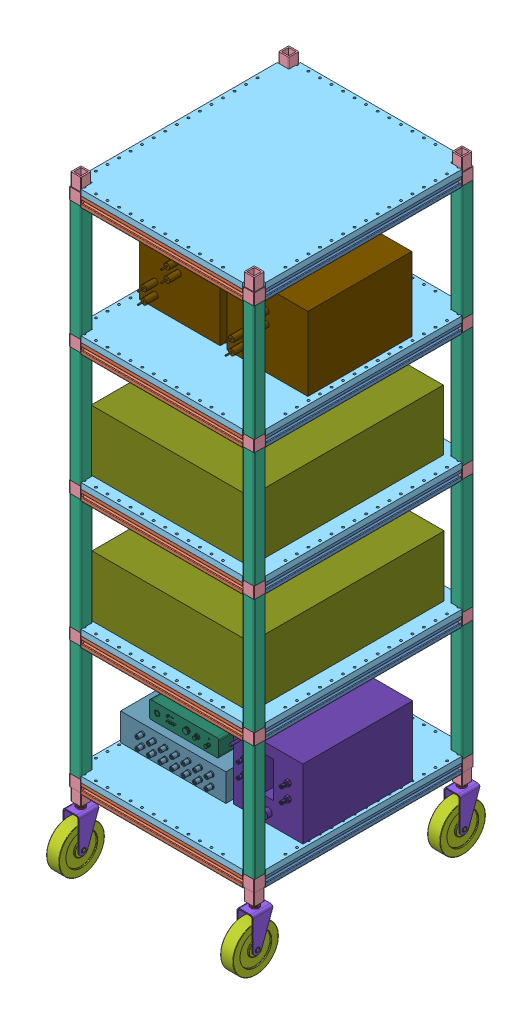
SolidWorks assembly Frame V2, configuration Default. Lengths in mm.
Overall size (421.16 1328.12 562.5).
122 component instances, 18 part files, 99 mates.
Components (placement in the parent):
- Rack Level V2-1: Rack Level V2 [Default] at (-142.0534 42.1379 2.242) size (406.56 81.28 482.6)
  - connector_rod_17in-1: connector_rod_17in [Default] at (244.6451 248.7296 254.5249) size (25.4 25.4 431.8)
  - connector_rod_17in-2: connector_rod_17in [Default] at (623.9342 246.0174 254.5249) size (25.4 25.4 431.8)
  - connector_rod_14in-1: connector_rod_14in [Default] at (435.1457 246.5198 483.1249) x (0 0 -1) z (1 0 0) size (25.4 25.4 355.6)
  - connector_rod_14in-2: connector_rod_14in [Default] at (434.9859 248.2272 25.9249) x (0 0 -1) z (1 0 0) size (25.4 25.4 355.6)
  - corner_bracket8-1: corner_bracket8 [Default] at (257.3451 248.4784 38.6249) x (0 1 0) z (1 0 0) size (17 21.5 21.5)
  - corner_bracket8-3: corner_bracket8 [Default] at (257.3451 248.9808 470.4249) x (0 1 0) z (0 0 -1) size (17 21.5 21.5)
  - corner_bracket8-4: corner_bracket8 [Default] at (611.2342 245.7662 38.6249) x (0 1 0) z (0 0 1) size (17 21.5 21.5)
  - corner_bracket8-5: corner_bracket8 [Default] at (611.2342 246.2686 470.4249) x (0 -1 0) z (0 0 -1) size (17 21.5 21.5)
  - 9215-1: 9215 [Default] at (625.4859 250.333 25.9249) x (0 1 0) z (0 0 1) size (81.28 25.4 25.4)
  - 9215-2: 9215 [Default] at (244.4859 250.333 25.9249) x (0 1 0) z (0 0 1) size (81.28 25.4 25.4)
  - 9215-3: 9215 [Default] at (244.6457 250.333 483.1249) x (0 1 0) z (0 0 1) size (81.28 25.4 25.4)
  - 9215-4: 9215 [Default] at (625.6457 250.333 483.1249) x (0 1 0) z (0 0 1) size (81.28 25.4 25.4)
- Rack Floor-1: Rack Floor [Default] at (294.7433 300.8553 258.4179) x (0 0 -1) z (1 0 0) size (482.6 12.7 406.4)
- 9000_10_CL-1: 9000_10_CL [Default] at (483.5923 559.171 485.3669) x (1 0 0) z (0 1 0) size (25.4 25.4 254)
- 9000_10_CL-2: 9000_10_CL [Default] at (483.4325 559.171 28.1669) x (1 0 0) z (0 1 0) size (25.4 25.4 254)
- 9000_10_CL-3: 9000_10_CL [Default] at (102.5923 559.171 485.3669) x (1 0 0) z (0 1 0) size (25.4 25.4 254)
- 9000_10_CL-7: 9000_10_CL [Default] at (102.4325 305.171 28.1669) x (1 0 0) z (0 -1 0) size (25.4 25.4 254)
- Assem Wheele-1: Assem Wheele [Default] at (60.7885 133.8168 -43.4718) x (1 0 0) z (0 0.022835 0.999739) size (40 156.51 100)
  - Wheel s-1: Wheel s [Default] at (42.518 38.0039 83.6543) size (28 100 100)
  - Brackets-1: Brackets [Default] at (42.518 28.7828 49.4348) x (1 0 0) z (0 -0.022835 0.999739) size (34.6 79.05 44)
  - Brussh-1: Brussh [Default] at (42.518 38.0039 83.6543) x (0 1 0) z (0 0 1) size (13.95 28 13.95)
  - Circlips-1: Circlips [Default] at (60.5355 38.0039 83.6543) x (0 0 -1) z (1 0 0) size (9.65 8.99 0.64)
  - Postt-1: Postt [Default] at (42.518 101.3114 73.0971) x (0.999012 -0.001015 0.044435) z (-0.044446 -0.022812 0.998751) size (18 43 18)
  - Shafts-1: Shafts [Default] at (23.218 38.0039 83.6543) x (0 0.999739 0.022835) z (0 -0.022835 0.999739) size (16 40 16)
- Assem Wheele-4: Assem Wheele [Default] at (60.9483 133.8168 415.4762) x (1 0 0) z (0 0.022835 0.999739) size (40 156.51 100)
  - Wheel s-1: Wheel s [Default] at (42.518 38.0039 83.6543) size (28 100 100)
  - Brackets-1: Brackets [Default] at (42.518 28.7828 49.4348) x (1 0 0) z (0 -0.022835 0.999739) size (34.6 79.05 44)
  - Brussh-1: Brussh [Default] at (42.518 38.0039 83.6543) x (0 1 0) z (0 0 1) size (13.95 28 13.95)
  - Circlips-1: Circlips [Default] at (60.5355 38.0039 83.6543) x (0 0 -1) z (1 0 0) size (9.65 8.99 0.64)
  - Postt-1: Postt [Default] at (42.518 101.3114 73.0971) x (0.999012 -0.001015 0.044435) z (-0.044446 -0.022812 0.998751) size (18 43 18)
  - Shafts-1: Shafts [Default] at (23.218 38.0039 83.6543) x (0 0.999739 0.022835) z (0 -0.022835 0.999739) size (16 40 16)
- Assem Wheele-5: Assem Wheele [Default] at (441.9483 133.8168 413.7282) x (1 0 0) z (0 0.022835 0.999739) size (40 156.51 100)
  - Wheel s-1: Wheel s [Default] at (42.518 38.0039 83.6543) size (28 100 100)
  - Brackets-1: Brackets [Default] at (42.518 28.7828 49.4348) x (1 0 0) z (0 -0.022835 0.999739) size (34.6 79.05 44)
  - Brussh-1: Brussh [Default] at (42.518 38.0039 83.6543) x (0 1 0) z (0 0 1) size (13.95 28 13.95)
  - Circlips-1: Circlips [Default] at (60.5355 38.0039 83.6543) x (0 0 -1) z (1 0 0) size (9.65 8.99 0.64)
  - Postt-1: Postt [Default] at (42.518 101.3114 73.0971) x (0.999012 -0.001015 0.044435) z (-0.044446 -0.022812 0.998751) size (18 43 18)
  - Shafts-1: Shafts [Default] at (23.218 38.0039 83.6543) x (0 0.999739 0.022835) z (0 -0.022835 0.999739) size (16 40 16)
- Assem Wheele-6: Assem Wheele [Default] at (440.0405 133.8168 -43.4718) x (1 0 0) z (0 0.022835 0.999739) size (40 156.51 100)
  - Wheel s-1: Wheel s [Default] at (42.518 38.0039 83.6543) size (28 100 100)
  - Brackets-1: Brackets [Default] at (42.518 28.7828 49.4348) x (1 0 0) z (0 -0.022835 0.999739) size (34.6 79.05 44)
  - Brussh-1: Brussh [Default] at (42.518 38.0039 83.6543) x (0 1 0) z (0 0 1) size (13.95 28 13.95)
  - Circlips-1: Circlips [Default] at (60.5355 38.0039 83.6543) x (0 0 -1) z (1 0 0) size (9.65 8.99 0.64)
  - Postt-1: Postt [Default] at (42.518 101.3114 73.0971) x (0.999012 -0.001015 0.044435) z (-0.044446 -0.022812 0.998751) size (18 43 18)
  - Shafts-1: Shafts [Default] at (23.218 38.0039 83.6543) x (0 0.999739 0.022835) z (0 -0.022835 0.999739) size (16 40 16)
- CD15_Carrier_Demodulator-1: CD15_Carrier_Demodulator [Default] at (219.1976 411.9803 266.4352) size (142.88 73.03 161.92)
- PowerLab_835-1: PowerLab_835 [Default] at (212.5296 313.5553 266.8747) size (231.78 60.32 263.58)
- BMA_200-2: BMA_200 [Default] at (219.2508 373.8803 275.2282) size (152.45 38.15 207.67)
- Rack Level V2-2: Rack Level V2 [Default] at (-142.0534 321.5379 2.242) size (406.56 81.28 482.6)
  - connector_rod_17in-1: connector_rod_17in [Default] at (244.6451 248.7296 254.5249) size (25.4 25.4 431.8)
  - connector_rod_17in-2: connector_rod_17in [Default] at (623.9342 246.0174 254.5249) size (25.4 25.4 431.8)
  - connector_rod_14in-1: connector_rod_14in [Default] at (435.1457 246.5198 483.1249) x (0 0 -1) z (1 0 0) size (25.4 25.4 355.6)
  - connector_rod_14in-2: connector_rod_14in [Default] at (434.9859 248.2272 25.9249) x (0 0 -1) z (1 0 0) size (25.4 25.4 355.6)
  - corner_bracket8-1: corner_bracket8 [Default] at (257.3451 248.4784 38.6249) x (0 1 0) z (1 0 0) size (17 21.5 21.5)
  - corner_bracket8-3: corner_bracket8 [Default] at (257.3451 248.9808 470.4249) x (0 1 0) z (0 0 -1) size (17 21.5 21.5)
  - corner_bracket8-4: corner_bracket8 [Default] at (611.2342 245.7662 38.6249) x (0 1 0) z (0 0 1) size (17 21.5 21.5)
  - corner_bracket8-5: corner_bracket8 [Default] at (611.2342 246.2686 470.4249) x (0 -1 0) z (0 0 -1) size (17 21.5 21.5)
  - 9215-1: 9215 [Default] at (625.4859 250.333 25.9249) x (0 1 0) z (0 0 1) size (81.28 25.4 25.4)
  - 9215-2: 9215 [Default] at (244.4859 250.333 25.9249) x (0 1 0) z (0 0 1) size (81.28 25.4 25.4)
  - 9215-3: 9215 [Default] at (244.6457 250.333 483.1249) x (0 1 0) z (0 0 1) size (81.28 25.4 25.4)
  - 9215-4: 9215 [Default] at (625.6457 250.333 483.1249) x (0 1 0) z (0 0 1) size (81.28 25.4 25.4)
- Rack Floor-2: Rack Floor [Default] at (294.7433 580.7577 258.4179) x (0 0 -1) z (1 0 0) size (482.6 12.7 406.4)
- O2_CO2_analyzer-2: O2_CO2_analyzer [Default] at (287.8054 593.4577 258.9533) x (0 0 1) z (-1 0 0) size (425.45 133.35 356.87)
- 9000_10_CL-8: 9000_10_CL [Default] at (483.4325 584.571 28.1669) x (1 0 0) z (0 -1 0) size (25.4 25.4 254)
- 9000_10_CL-9: 9000_10_CL [Default] at (102.4325 584.571 28.1669) x (1 0 0) z (0 -1 0) size (25.4 25.4 254)
- 9000_10_CL-11: 9000_10_CL [Default] at (483.5923 584.571 485.3669) x (1 0 0) z (0 -1 0) size (25.4 25.4 254)
- 9000_10_CL-12: 9000_10_CL [Default] at (102.5923 584.571 485.3669) x (1 0 0) z (0 -1 0) size (25.4 25.4 254)
- Flow_Control_R1-1: Flow_Control_R1 [Default] at (414.279 313.5553 264.2811) size (152.4 152.4 266.71)
- Rack Level V2-3: Rack Level V2 [Default] at (-142.0534 600.9379 2.242) size (406.56 81.28 482.6)
  - connector_rod_17in-1: connector_rod_17in [Default] at (244.6451 248.7296 254.5249) size (25.4 25.4 431.8)
  - connector_rod_17in-2: connector_rod_17in [Default] at (623.9342 246.0174 254.5249) size (25.4 25.4 431.8)
  - connector_rod_14in-1: connector_rod_14in [Default] at (435.1457 246.5198 483.1249) x (0 0 -1) z (1 0 0) size (25.4 25.4 355.6)
  - connector_rod_14in-2: connector_rod_14in [Default] at (434.9859 248.2272 25.9249) x (0 0 -1) z (1 0 0) size (25.4 25.4 355.6)
  - corner_bracket8-1: corner_bracket8 [Default] at (257.3451 248.4784 38.6249) x (0 1 0) z (1 0 0) size (17 21.5 21.5)
  - corner_bracket8-3: corner_bracket8 [Default] at (257.3451 248.9808 470.4249) x (0 1 0) z (0 0 -1) size (17 21.5 21.5)
  - corner_bracket8-4: corner_bracket8 [Default] at (611.2342 245.7662 38.6249) x (0 1 0) z (0 0 1) size (17 21.5 21.5)
  - corner_bracket8-5: corner_bracket8 [Default] at (611.2342 246.2686 470.4249) x (0 -1 0) z (0 0 -1) size (17 21.5 21.5)
  - 9215-1: 9215 [Default] at (625.4859 250.333 25.9249) x (0 1 0) z (0 0 1) size (81.28 25.4 25.4)
  - 9215-2: 9215 [Default] at (244.4859 250.333 25.9249) x (0 1 0) z (0 0 1) size (81.28 25.4 25.4)
  - 9215-3: 9215 [Default] at (244.6457 250.333 483.1249) x (0 1 0) z (0 0 1) size (81.28 25.4 25.4)
  - 9215-4: 9215 [Default] at (625.6457 250.333 483.1249) x (0 1 0) z (0 0 1) size (81.28 25.4 25.4)
- Rack Floor-3: Rack Floor [Default] at (294.7433 860.1577 258.4179) x (0 0 -1) z (1 0 0) size (482.6 12.7 406.4)
- O2_CO2_analyzer-3: O2_CO2_analyzer [Default] at (288.4244 872.8577 261.5371) x (0 0 1) z (-1 0 0) size (425.45 133.35 356.87)
- 9000_10_CL-13: 9000_10_CL [Default] at (102.5923 863.971 485.3669) x (1 0 0) z (0 -1 0) size (25.4 25.4 254)
- 9000_10_CL-14: 9000_10_CL [Default] at (102.4325 863.971 28.1669) x (1 0 0) z (0 -1 0) size (25.4 25.4 254)
- 9000_10_CL-15: 9000_10_CL [Default] at (483.4325 863.971 28.1669) x (1 0 0) z (0 -1 0) size (25.4 25.4 254)
- 9000_10_CL-16: 9000_10_CL [Default] at (483.5923 863.971 485.3669) x (1 0 0) z (0 -1 0) size (25.4 25.4 254)
- Rack Level V2-4: Rack Level V2 [Default] at (-142.0534 880.3379 2.242) size (406.56 81.28 482.6)
  - connector_rod_17in-1: connector_rod_17in [Default] at (244.6451 248.7296 254.5249) size (25.4 25.4 431.8)
  - connector_rod_17in-2: connector_rod_17in [Default] at (623.9342 246.0174 254.5249) size (25.4 25.4 431.8)
  - connector_rod_14in-1: connector_rod_14in [Default] at (435.1457 246.5198 483.1249) x (0 0 -1) z (1 0 0) size (25.4 25.4 355.6)
  - connector_rod_14in-2: connector_rod_14in [Default] at (434.9859 248.2272 25.9249) x (0 0 -1) z (1 0 0) size (25.4 25.4 355.6)
  - corner_bracket8-1: corner_bracket8 [Default] at (257.3451 248.4784 38.6249) x (0 1 0) z (1 0 0) size (17 21.5 21.5)
  - corner_bracket8-3: corner_bracket8 [Default] at (257.3451 248.9808 470.4249) x (0 1 0) z (0 0 -1) size (17 21.5 21.5)
  - corner_bracket8-4: corner_bracket8 [Default] at (611.2342 245.7662 38.6249) x (0 1 0) z (0 0 1) size (17 21.5 21.5)
  - corner_bracket8-5: corner_bracket8 [Default] at (611.2342 246.2686 470.4249) x (0 -1 0) z (0 0 -1) size (17 21.5 21.5)
  - 9215-1: 9215 [Default] at (625.4859 250.333 25.9249) x (0 1 0) z (0 0 1) size (81.28 25.4 25.4)
  - 9215-2: 9215 [Default] at (244.4859 250.333 25.9249) x (0 1 0) z (0 0 1) size (81.28 25.4 25.4)
  - 9215-3: 9215 [Default] at (244.6457 250.333 483.1249) x (0 1 0) z (0 0 1) size (81.28 25.4 25.4)
  - 9215-4: 9215 [Default] at (625.6457 250.333 483.1249) x (0 1 0) z (0 0 1) size (81.28 25.4 25.4)
- Rack Floor-4: Rack Floor [Default] at (294.7433 1139.5577 258.4179) x (0 0 -1) z (1 0 0) size (482.6 12.7 406.4)
- O2_CO2_sensor-1: O2_CO2_sensor [Default] at (199.963 1152.2577 251.1389) size (177.8 161.93 266.7)
- O2_CO2_sensor-2: O2_CO2_sensor [Default] at (393.0313 1152.2577 251.2283) size (177.8 161.93 266.7)
- 9000_10_CL-17: 9000_10_CL [Default] at (102.5923 1143.371 485.3669) x (1 0 0) z (0 -1 0) size (25.4 25.4 254)
- 9000_10_CL-18: 9000_10_CL [Default] at (483.5923 1143.371 485.3669) x (1 0 0) z (0 -1 0) size (25.4 25.4 254)
- 9000_10_CL-19: 9000_10_CL [Default] at (102.4325 1143.371 28.1669) x (1 0 0) z (0 -1 0) size (25.4 25.4 254)
- 9000_10_CL-20: 9000_10_CL [Default] at (483.4325 1143.371 28.1669) x (1 0 0) z (0 -1 0) size (25.4 25.4 254)
- Rack Level V2-5: Rack Level V2 [Default] at (-142.0534 1159.7379 2.242) size (406.56 81.28 482.6)
  - connector_rod_17in-1: connector_rod_17in [Default] at (244.6451 248.7296 254.5249) size (25.4 25.4 431.8)
  - connector_rod_17in-2: connector_rod_17in [Default] at (623.9342 246.0174 254.5249) size (25.4 25.4 431.8)
  - connector_rod_14in-1: connector_rod_14in [Default] at (435.1457 246.5198 483.1249) x (0 0 -1) z (1 0 0) size (25.4 25.4 355.6)
  - connector_rod_14in-2: connector_rod_14in [Default] at (434.9859 248.2272 25.9249) x (0 0 -1) z (1 0 0) size (25.4 25.4 355.6)
  - corner_bracket8-1: corner_bracket8 [Default] at (257.3451 248.4784 38.6249) x (0 1 0) z (1 0 0) size (17 21.5 21.5)
  - corner_bracket8-3: corner_bracket8 [Default] at (257.3451 248.9808 470.4249) x (0 1 0) z (0 0 -1) size (17 21.5 21.5)
  - corner_bracket8-4: corner_bracket8 [Default] at (611.2342 245.7662 38.6249) x (0 1 0) z (0 0 1) size (17 21.5 21.5)
  - corner_bracket8-5: corner_bracket8 [Default] at (611.2342 246.2686 470.4249) x (0 -1 0) z (0 0 -1) size (17 21.5 21.5)
  - 9215-1: 9215 [Default] at (625.4859 250.333 25.9249) x (0 1 0) z (0 0 1) size (81.28 25.4 25.4)
  - 9215-2: 9215 [Default] at (244.4859 250.333 25.9249) x (0 1 0) z (0 0 1) size (81.28 25.4 25.4)
  - 9215-3: 9215 [Default] at (244.6457 250.333 483.1249) x (0 1 0) z (0 0 1) size (81.28 25.4 25.4)
  - 9215-4: 9215 [Default] at (625.6457 250.333 483.1249) x (0 1 0) z (0 0 1) size (81.28 25.4 25.4)
- Rack Floor-5: Rack Floor [Default] at (294.7433 1418.9577 258.4179) x (0 0 -1) z (1 0 0) size (482.6 12.7 406.4)
Mates (geometry in assembly coordinates):
- Coincident1: coincident anti-aligned: plane of Rack Level V2-1/9215-4 through (472.5433 333.111 475.5879) normal (-1 0 0); plane of Rack Floor-1 through (472.5433 300.8553 499.7179) normal (1 0 0)
- Coincident2: coincident anti-aligned: plane of Rack Level V2-1/9215-4 through (493.3713 333.111 474.3179) normal (0 0 -1); plane of Rack Floor-1 through (497.9433 300.8553 474.3179) normal (0 0 1)
- Parallel1: parallel anti-aligned: plane of Rack Level V2-1/9215-1 through (473.6535 333.111 39.2159) normal (0 0 1); plane of Rack Floor-1 through (497.9433 300.8553 42.5179) normal (0 0 -1)
- Parallel2: parallel anti-aligned: plane of Rack Level V2-1/9215-1 through (472.3835 333.111 18.3879) normal (-1 0 0); plane of Rack Floor-1 through (472.5433 300.8553 17.1179) normal (1 0 0)
- Coincident7: coincident anti-aligned: plane of Rack Level V2-1/9215-4 through (495.0223 305.171 496.7969) normal (0 1 0); plane of 9000_10_CL-1 through (473.0005 305.171 495.9587) normal (0 -1 0)
- Coincident8: coincident aligned: plane of Rack Level V2-1/9215-4 through (472.1623 305.171 498.0669) normal (0 0 1); plane of 9000_10_CL-1 through (473.0005 305.171 498.0669) normal (0 0 1)
- Coincident13: coincident anti-aligned: plane of Rack Level V2-1/9215-1 through (494.8625 305.171 39.5969) normal (0 1 0); plane of 9000_10_CL-2 through (472.8407 305.171 38.7587) normal (0 -1 0)
- Coincident14: coincident aligned: plane of Rack Level V2-1/9215-1 through (470.7325 305.171 16.7369) normal (-1 0 0); plane of 9000_10_CL-2 through (470.7325 305.171 17.5751) normal (-1 0 0)
- Coincident15: coincident aligned: plane of Rack Level V2-1/9215-1 through (494.8625 305.171 15.4669) normal (0 0 -1); plane of 9000_10_CL-2 through (494.0243 305.171 15.4669) normal (0 0 -1)
- Coincident16: coincident aligned: plane of Rack Level V2-1/9215-4 through (472.1623 305.171 498.0669) normal (0 0 1); plane of 9000_10_CL-1 through (473.0005 305.171 498.0669) normal (0 0 1)
- Coincident17: coincident aligned: plane of Rack Level V2-1/9215-4 through (496.2923 305.171 496.7969) normal (1 0 0); plane of 9000_10_CL-1 through (496.2923 305.171 495.9587) normal (1 0 0)
- Coincident18: coincident anti-aligned: plane of Rack Level V2-1/9215-3 through (114.0223 305.171 496.7969) normal (0 1 0); plane of 9000_10_CL-3 through (92.0005 305.171 495.9587) normal (0 -1 0)
- Coincident19: coincident aligned: plane of Rack Level V2-1/9215-3 through (91.1623 305.171 498.0669) normal (0 0 1); plane of 9000_10_CL-3 through (92.0005 305.171 498.0669) normal (0 0 1)
- Coincident20: coincident aligned: plane of Rack Level V2-1/9215-3 through (89.8923 305.171 473.9369) normal (-1 0 0); plane of 9000_10_CL-3 through (89.8923 305.171 474.7751) normal (-1 0 0)
- Coincident21: coincident anti-aligned: plane of Rack Level V2-1/9215-2 through (113.8625 305.171 39.5969) normal (0 1 0); plane of 9000_10_CL-7 through (91.8407 305.171 17.5751) normal (0 -1 0)
- Coincident22: coincident aligned: plane of Rack Level V2-1/9215-2 through (89.7325 305.171 16.7369) normal (-1 0 0); plane of 9000_10_CL-7 through (89.7325 559.171 38.7587) normal (-1 0 0)
- Coincident23: coincident aligned: plane of Rack Level V2-1/9215-2 through (113.8625 305.171 15.4669) normal (0 0 -1); plane of 9000_10_CL-7 through (91.8407 559.171 15.4669) normal (0 0 -1)
- Coincident24: coincident anti-aligned: plane of Rack Level V2-1/9215-2 through (113.8625 279.771 39.5969) normal (0 -1 0); plane of Assem Wheele-1/Postt-1 through (110.2996 279.771 27.604) normal (0 1 0)
- Tangent1: tangent anti-aligned: plane of Rack Level V2-1/9215-2 through (110.3065 333.111 36.0409) normal (-1 0 0); cylinder of Assem Wheele-1/Postt-1 through (103.3065 279.771 27.2929) axis (0 1 0) radius 7
- Tangent2: tangent anti-aligned: plane of Rack Level V2-1/9215-2 through (110.3065 333.111 20.2929) normal (0 0 1); cylinder of Assem Wheele-1/Postt-1 through (103.3065 279.771 27.2929) axis (0 1 0) radius 7
- Coincident27: coincident anti-aligned: plane of Rack Level V2-1/9215-3 through (114.0223 279.771 496.7969) normal (0 -1 0); plane of Assem Wheele-4/Postt-1 through (110.4594 279.771 486.552) normal (0 1 0)
- Tangent9: tangent anti-aligned: plane of Rack Level V2-1/9215-3 through (110.4663 333.111 493.2409) normal (-1 0 0); cylinder of Assem Wheele-4/Postt-1 through (103.4663 279.771 486.2409) axis (0 1 0) radius 7
- Tangent10: tangent anti-aligned: plane of Rack Level V2-1/9215-3 through (94.7183 333.111 493.2409) normal (0 0 -1); cylinder of Assem Wheele-4/Postt-1 through (103.4663 279.771 486.2409) axis (0 1 0) radius 7
- Coincident28: coincident anti-aligned: plane of Rack Level V2-1/9215-4 through (495.0223 279.771 496.7969) normal (0 -1 0); plane of Assem Wheele-5/Postt-1 through (491.4594 279.771 484.804) normal (0 1 0)
- Tangent11: tangent anti-aligned: plane of Rack Level V2-1/9215-4 through (491.4663 333.111 493.2409) normal (-1 0 0); cylinder of Assem Wheele-5/Postt-1 through (484.4663 279.771 484.4929) axis (0 1 0) radius 7
- Tangent12: tangent anti-aligned: plane of Rack Level V2-1/9215-4 through (491.4663 333.111 477.4929) normal (0 0 1); cylinder of Assem Wheele-5/Postt-1 through (484.4663 279.771 484.4929) axis (0 1 0) radius 7
- Coincident29: coincident anti-aligned: plane of Rack Level V2-1/9215-1 through (494.8625 279.771 39.5969) normal (0 -1 0); plane of Assem Wheele-6/Postt-1 through (489.5516 279.771 27.604) normal (0 1 0)
- Tangent13: tangent anti-aligned: plane of Rack Level V2-1/9215-1 through (491.3065 333.111 20.2929) normal (0 0 1); cylinder of Assem Wheele-6/Postt-1 through (482.5585 279.771 27.2929) axis (0 1 0) radius 7
- Tangent14: tangent anti-aligned: plane of Rack Level V2-1/9215-1 through (475.5585 333.111 20.2929) normal (1 0 0); cylinder of Assem Wheele-6/Postt-1 through (482.5585 279.771 27.2929) axis (0 1 0) radius 7
- Parallel5: parallel anti-aligned: plane of Rack Level V2-1/9215-1 through (470.7325 305.171 16.7369) normal (-1 0 0); plane of Rack Floor-1 through (472.5433 300.8553 17.1179) normal (1 0 0)
- Coincident33: coincident anti-aligned: plane of Rack Floor-1 through (294.7433 313.5553 258.4179) normal (0 1 0); plane of PowerLab_835-1 through (212.5296 313.5553 266.8747) normal (0 -1 0)
- Coincident34: coincident anti-aligned: plane of PowerLab_835-1 through (212.5296 373.8803 266.8747) normal (0 1 0); plane of BMA_200-2 through (219.2508 373.8803 275.2282) normal (0 -1 0)
- Coincident35: coincident anti-aligned: plane of CD15_Carrier_Demodulator-1 through (219.1976 411.9803 266.4352) normal (0 -1 0); plane of BMA_200-2 through (219.2508 411.9803 275.2282) normal (0 1 0)
- Coincident36: coincident anti-aligned: plane of Rack Level V2-1/connector_rod_17in-2 through (477.5247 300.8553 472.6669) normal (0 1 0); plane of Rack Floor-1 through (294.7433 300.8553 258.4179) normal (0 -1 0)
- Coincident37: coincident anti-aligned: plane of 9000_10_CL-1 through (473.0005 559.171 495.9587) normal (0 1 0); plane of Rack Level V2-2/9215-4 through (495.0223 559.171 496.7969) normal (0 -1 0)
- Coincident38: coincident aligned: plane of 9000_10_CL-1 through (496.2923 305.171 495.9587) normal (1 0 0); plane of Rack Level V2-2/9215-4 through (496.2923 584.571 496.7969) normal (1 0 0)
- Coincident39: coincident aligned: plane of 9000_10_CL-1 through (473.0005 305.171 498.0669) normal (0 0 1); plane of Rack Level V2-2/9215-4 through (472.1623 584.571 498.0669) normal (0 0 1)
- Coincident40: coincident anti-aligned: plane of Rack Level V2-2/9215-4 through (472.5433 612.511 475.5879) normal (-1 0 0); plane of Rack Floor-2 through (472.5433 580.7577 499.7179) normal (1 0 0)
- Coincident41: coincident anti-aligned: plane of Rack Level V2-2/9215-4 through (493.3713 612.511 474.3179) normal (0 0 -1); plane of Rack Floor-2 through (497.9433 580.7577 474.3179) normal (0 0 1)
- Coincident42: coincident anti-aligned: plane of Rack Level V2-2/connector_rod_14in-1 through (470.8923 580.7577 489.723) normal (0 1 0); plane of Rack Floor-2 through (294.7433 580.7577 258.4179) normal (0 -1 0)
- Coincident43: coincident anti-aligned: plane of Rack Floor-2 through (294.7433 593.4577 258.4179) normal (0 1 0); plane of O2_CO2_analyzer-2 through (287.8054 593.4577 258.9533) normal (0 -1 0)
- Coincident52: coincident anti-aligned: plane of Rack Level V2-2/9215-3 through (114.0223 584.571 496.7969) normal (0 1 0); plane of 9000_10_CL-12 through (92.0005 584.571 474.7751) normal (0 -1 0)
- Coincident53: coincident aligned: plane of Rack Level V2-2/9215-3 through (91.1623 584.571 498.0669) normal (0 0 1); plane of 9000_10_CL-12 through (113.1841 838.571 498.0669) normal (0 0 1)
- Coincident54: coincident aligned: plane of Rack Level V2-2/9215-3 through (89.8923 584.571 473.9369) normal (-1 0 0); plane of 9000_10_CL-12 through (89.8923 838.571 495.9587) normal (-1 0 0)
- Coincident55: coincident anti-aligned: plane of Rack Level V2-2/9215-4 through (495.0223 584.571 496.7969) normal (0 1 0); plane of 9000_10_CL-11 through (473.0005 584.571 474.7751) normal (0 -1 0)
- Coincident56: coincident aligned: plane of Rack Level V2-2/9215-4 through (472.1623 584.571 498.0669) normal (0 0 1); plane of 9000_10_CL-11 through (494.1841 838.571 498.0669) normal (0 0 1)
- Coincident57: coincident aligned: plane of Rack Level V2-2/9215-4 through (496.2923 584.571 496.7969) normal (1 0 0); plane of 9000_10_CL-11 through (496.2923 838.571 474.7751) normal (1 0 0)
- Coincident58: coincident anti-aligned: plane of Rack Level V2-2/9215-1 through (494.8625 584.571 39.5969) normal (0 1 0); plane of 9000_10_CL-8 through (472.8407 584.571 17.5751) normal (0 -1 0)
- Coincident59: coincident aligned: plane of Rack Level V2-2/9215-1 through (494.8625 584.571 15.4669) normal (0 0 -1); plane of 9000_10_CL-8 through (472.8407 838.571 15.4669) normal (0 0 -1)
- Coincident60: coincident aligned: plane of Rack Level V2-2/9215-1 through (496.1325 584.571 39.5969) normal (1 0 0); plane of 9000_10_CL-8 through (496.1325 838.571 17.5751) normal (1 0 0)
- Coincident61: coincident anti-aligned: plane of Rack Level V2-2/9215-2 through (113.8625 584.571 39.5969) normal (0 1 0); plane of 9000_10_CL-9 through (91.8407 584.571 17.5751) normal (0 -1 0)
- Coincident62: coincident aligned: plane of Rack Level V2-2/9215-2 through (89.7325 584.571 16.7369) normal (-1 0 0); plane of 9000_10_CL-9 through (89.7325 838.571 38.7587) normal (-1 0 0)
- Coincident63: coincident aligned: plane of Rack Level V2-2/9215-2 through (113.8625 584.571 15.4669) normal (0 0 -1); plane of 9000_10_CL-9 through (91.8407 838.571 15.4669) normal (0 0 -1)
- Coincident64: coincident anti-aligned: plane of Rack Floor-1 through (294.7433 313.5553 258.4179) normal (0 1 0); plane of Flow_Control_R1-1 through (414.279 313.5553 264.2811) normal (0 -1 0)
- Coincident65: coincident anti-aligned: plane of 9000_10_CL-12 through (92.0005 838.571 474.7751) normal (0 1 0); plane of Rack Level V2-3/9215-3 through (114.0223 838.571 496.7969) normal (0 -1 0)
- Coincident66: coincident aligned: plane of 9000_10_CL-12 through (113.1841 838.571 498.0669) normal (0 0 1); plane of Rack Level V2-3/9215-3 through (91.1623 863.971 498.0669) normal (0 0 1)
- Coincident67: coincident aligned: plane of 9000_10_CL-12 through (89.8923 838.571 495.9587) normal (-1 0 0); plane of Rack Level V2-3/9215-3 through (89.8923 863.971 473.9369) normal (-1 0 0)
- Coincident68: coincident anti-aligned: plane of Rack Level V2-3/9215-4 through (493.3713 891.911 474.3179) normal (0 0 -1); plane of Rack Floor-3 through (497.9433 860.1577 474.3179) normal (0 0 1)
- Coincident69: coincident anti-aligned: plane of Rack Level V2-3/9215-4 through (472.5433 891.911 475.5879) normal (-1 0 0); plane of Rack Floor-3 through (472.5433 860.1577 499.7179) normal (1 0 0)
- Coincident70: coincident anti-aligned: plane of Rack Level V2-3/connector_rod_14in-1 through (470.8923 860.1577 489.723) normal (0 1 0); plane of Rack Floor-3 through (294.7433 860.1577 258.4179) normal (0 -1 0)
- Coincident71: coincident anti-aligned: plane of Rack Floor-3 through (294.7433 872.8577 258.4179) normal (0 1 0); plane of O2_CO2_analyzer-3 through (288.4244 872.8577 261.5371) normal (0 -1 0)
- Coincident72: coincident anti-aligned: plane of Rack Level V2-3/9215-3 through (114.0223 863.971 496.7969) normal (0 1 0); plane of 9000_10_CL-13 through (92.0005 863.971 474.7751) normal (0 -1 0)
- Coincident73: coincident aligned: plane of Rack Level V2-3/9215-3 through (91.1623 863.971 498.0669) normal (0 0 1); plane of 9000_10_CL-13 through (113.1841 1117.971 498.0669) normal (0 0 1)
- Coincident74: coincident aligned: plane of Rack Level V2-3/9215-3 through (89.8923 863.971 473.9369) normal (-1 0 0); plane of 9000_10_CL-13 through (89.8923 1117.971 495.9587) normal (-1 0 0)
- Coincident76: coincident: plane of Rack Level V2-3/9215-1 through (494.8625 863.971 39.5969) normal (0 1 0); plane of 9000_10_CL-15 through (472.8407 863.971 17.5751) normal (0 -1 0)
- Coincident77: coincident: plane of Rack Level V2-3/9215-1 through (496.1325 863.971 39.5969) normal (1 0 0); plane of 9000_10_CL-15 through (496.1325 1117.971 17.5751) normal (1 0 0)
- Coincident78: coincident aligned: plane of Rack Level V2-3/9215-1 through (494.8625 863.971 15.4669) normal (0 0 -1); plane of 9000_10_CL-15 through (472.8407 1117.971 15.4669) normal (0 0 -1)
- Coincident79: coincident: plane of Rack Level V2-3/9215-4 through (495.0223 863.971 496.7969) normal (0 1 0); plane of 9000_10_CL-16 through (473.0005 863.971 474.7751) normal (0 -1 0)
- Coincident80: coincident: plane of Rack Level V2-3/9215-4 through (496.2923 863.971 496.7969) normal (1 0 0); plane of 9000_10_CL-16 through (496.2923 1117.971 474.7751) normal (1 0 0)
- Coincident81: coincident aligned: plane of Rack Level V2-3/9215-4 through (472.1623 863.971 498.0669) normal (0 0 1); plane of 9000_10_CL-16 through (494.1841 1117.971 498.0669) normal (0 0 1)
- Coincident82: coincident: plane of Rack Level V2-3/9215-2 through (113.8625 863.971 39.5969) normal (0 1 0); plane of 9000_10_CL-14 through (91.8407 863.971 17.5751) normal (0 -1 0)
- Coincident83: coincident: plane of Rack Level V2-3/9215-2 through (89.7325 863.971 16.7369) normal (-1 0 0); plane of 9000_10_CL-14 through (89.7325 1117.971 38.7587) normal (-1 0 0)
- Coincident84: coincident aligned: plane of Rack Level V2-3/9215-2 through (113.8625 863.971 15.4669) normal (0 0 -1); plane of 9000_10_CL-14 through (91.8407 1117.971 15.4669) normal (0 0 -1)
- Coincident85: coincident: plane of 9000_10_CL-14 through (91.8407 1117.971 17.5751) normal (0 1 0); plane of Rack Level V2-4/9215-2 through (113.8625 1117.971 39.5969) normal (0 -1 0)
- Coincident86: coincident: plane of 9000_10_CL-14 through (89.7325 1117.971 38.7587) normal (-1 0 0); plane of Rack Level V2-4/9215-2 through (89.7325 1143.371 16.7369) normal (-1 0 0)
- Coincident87: coincident aligned: plane of 9000_10_CL-14 through (91.8407 1117.971 15.4669) normal (0 0 -1); plane of Rack Level V2-4/9215-2 through (113.8625 1143.371 15.4669) normal (0 0 -1)
- Coincident88: coincident: plane of Rack Level V2-4/9215-4 through (493.3713 1171.311 474.3179) normal (0 0 -1); plane of Rack Floor-4 through (497.9433 1139.5577 474.3179) normal (0 0 1)
- Coincident89: coincident: plane of Rack Level V2-4/9215-4 through (472.5433 1171.311 475.5879) normal (-1 0 0); plane of Rack Floor-4 through (472.5433 1139.5577 499.7179) normal (1 0 0)
- Coincident90: coincident anti-aligned: plane of Rack Level V2-4/connector_rod_14in-1 through (470.8923 1139.5577 489.723) normal (0 1 0); plane of Rack Floor-4 through (294.7433 1139.5577 258.4179) normal (0 -1 0)
- Coincident91: coincident anti-aligned: plane of Rack Floor-4 through (294.7433 1152.2577 258.4179) normal (0 1 0); plane of O2_CO2_sensor-1 through (199.963 1152.2577 251.1389) normal (0 -1 0)
- Coincident92: coincident anti-aligned: plane of Rack Floor-4 through (294.7433 1152.2577 258.4179) normal (0 1 0); plane of O2_CO2_sensor-2 through (393.0313 1152.2577 251.2283) normal (0 -1 0)
- Coincident93: coincident: plane of Rack Level V2-4/9215-3 through (114.0223 1143.371 496.7969) normal (0 1 0); plane of 9000_10_CL-17 through (92.0005 1143.371 474.7751) normal (0 -1 0)
- Coincident94: coincident: plane of Rack Level V2-4/9215-3 through (91.1623 1143.371 498.0669) normal (0 0 1); plane of 9000_10_CL-17 through (113.1841 1397.371 498.0669) normal (0 0 1)
- Coincident95: coincident aligned: plane of Rack Level V2-4/9215-3 through (89.8923 1143.371 473.9369) normal (-1 0 0); plane of 9000_10_CL-17 through (89.8923 1397.371 495.9587) normal (-1 0 0)
- Coincident96: coincident: plane of Rack Level V2-4/9215-4 through (495.0223 1143.371 496.7969) normal (0 1 0); plane of 9000_10_CL-18 through (473.0005 1143.371 474.7751) normal (0 -1 0)
- Coincident97: coincident: plane of Rack Level V2-4/9215-4 through (472.1623 1143.371 498.0669) normal (0 0 1); plane of 9000_10_CL-18 through (494.1841 1397.371 498.0669) normal (0 0 1)
- Coincident98: coincident aligned: plane of Rack Level V2-4/9215-4 through (496.2923 1143.371 496.7969) normal (1 0 0); plane of 9000_10_CL-18 through (496.2923 1397.371 474.7751) normal (1 0 0)
- Coincident99: coincident: plane of Rack Level V2-4/9215-1 through (494.8625 1143.371 39.5969) normal (0 1 0); plane of 9000_10_CL-20 through (472.8407 1143.371 17.5751) normal (0 -1 0)
- Coincident100: coincident: plane of Rack Level V2-4/9215-1 through (496.1325 1143.371 39.5969) normal (1 0 0); plane of 9000_10_CL-20 through (496.1325 1397.371 17.5751) normal (1 0 0)
- Coincident101: coincident aligned: plane of Rack Level V2-4/9215-1 through (494.8625 1143.371 15.4669) normal (0 0 -1); plane of 9000_10_CL-20 through (472.8407 1397.371 15.4669) normal (0 0 -1)
- Coincident102: coincident: plane of Rack Level V2-4/9215-2 through (113.8625 1143.371 39.5969) normal (0 1 0); plane of 9000_10_CL-19 through (91.8407 1143.371 17.5751) normal (0 -1 0)
- Coincident103: coincident: plane of Rack Level V2-4/9215-2 through (89.7325 1143.371 16.7369) normal (-1 0 0); plane of 9000_10_CL-19 through (89.7325 1397.371 38.7587) normal (-1 0 0)
- Coincident104: coincident aligned: plane of Rack Level V2-4/9215-2 through (113.8625 1143.371 15.4669) normal (0 0 -1); plane of 9000_10_CL-19 through (91.8407 1397.371 15.4669) normal (0 0 -1)
- Coincident105: coincident: plane of 9000_10_CL-18 through (473.0005 1397.371 474.7751) normal (0 1 0); plane of Rack Level V2-5/9215-4 through (495.0223 1397.371 496.7969) normal (0 -1 0)
- Coincident106: coincident: plane of 9000_10_CL-18 through (496.2923 1397.371 474.7751) normal (1 0 0); plane of Rack Level V2-5/9215-4 through (496.2923 1422.771 496.7969) normal (1 0 0)
- Coincident107: coincident aligned: plane of 9000_10_CL-18 through (494.1841 1397.371 498.0669) normal (0 0 1); plane of Rack Level V2-5/9215-4 through (472.1623 1422.771 498.0669) normal (0 0 1)
- Coincident108: coincident: plane of Rack Level V2-5/9215-4 through (493.3713 1450.711 474.3179) normal (0 0 -1); plane of Rack Floor-5 through (497.9433 1418.9577 474.3179) normal (0 0 1)
- Coincident109: coincident: plane of Rack Level V2-5/9215-4 through (472.5433 1450.711 475.5879) normal (-1 0 0); plane of Rack Floor-5 through (472.5433 1418.9577 499.7179) normal (1 0 0)
- Coincident110: coincident anti-aligned: plane of Rack Level V2-5/connector_rod_14in-1 through (470.8923 1418.9577 489.723) normal (0 1 0); plane of Rack Floor-5 through (294.7433 1418.9577 258.4179) normal (0 -1 0)
